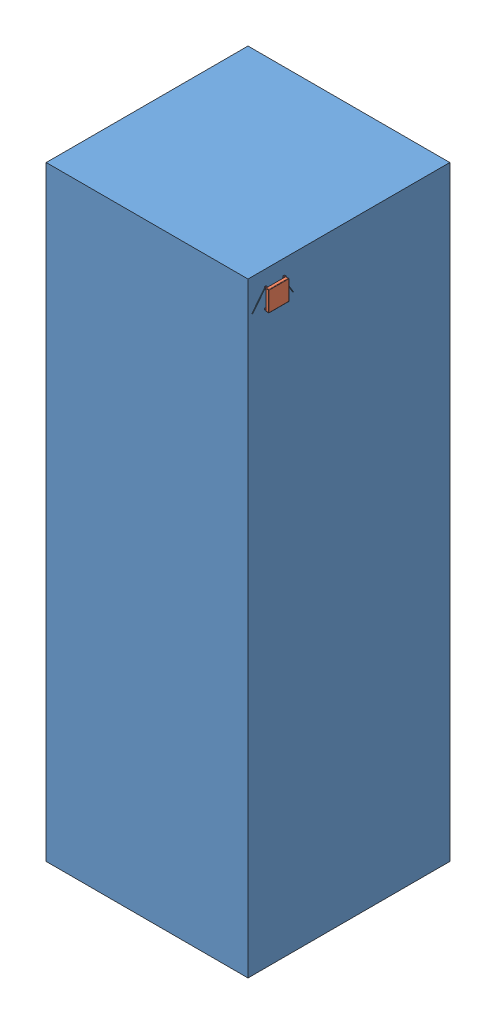
SolidWorks assembly with_building, configuration Default. Lengths in mm.
Overall size (10270 30000 10000).
10 component instances, 5 part files, 4 mates.
Components (placement in the parent):
- gedung-1: gedung [Default] at (-1.2528 -15032.5087 22.747) size (10000 30000 10000)
- full_coreXY_ass-1: full_coreXY_ass [Default] at (5184.5696 13734.8256 3801.1305) x (0 0 1) z (0 1 0) size (2041.12 273.73 1048.26) (flexible)
  - body-1: body [Default] at (-44.1875 -65.8225 17.0821) size (1000 150 1000)
  - brush-1: brush [Default] at (-44.1875 34.1775 17.0821) x (0.681029 0 -0.732256) z (-0.732256 0 -0.681029) size (741.72 210 741.72)
  - swivel-1: swivel [Default] at (377.6119 -153.5116 -450.8674) size (121.23 123.73 64.1)
  - swivel-2: swivel [Default] at (377.6119 -153.5116 485.0302) size (121.23 123.73 64.1)
  - swivel-6: swivel [Default] at (-546.5145 -153.5116 -450.8674) size (121.23 123.73 64.1)
  - swivel-7: swivel [Default] at (-546.5145 -153.5116 485.0302) size (121.23 123.73 64.1)
  - wiper-1: wiper [Default] at (714.4345 -185.8225 34.9173) x (0.615715 0 -0.787969) z (0.787969 0 0.615715) size (1000 220 20)
  - wiper-2: wiper [Default] at (-749.463 -185.8225 -1.3256) x (-0.505723 0 -0.862696) z (0.862696 0 -0.505723) size (1000 220 20)
Mates (geometry in assembly coordinates):
- Parallel1: parallel aligned: plane of gedung-1 through (-1.2528 14967.4913 22.747) normal (0 1 0); plane of full_coreXY_ass-1/body-1 through (5268.7472 14251.9077 3256.943) normal (0 1 0)
- Coincident2: coincident anti-aligned: plane of gedung-1 through (4998.7472 14967.4913 -4977.253) normal (1 0 0); plane of full_coreXY_ass-1/wiper-2 through (4998.7472 13733.5 3051.6675) normal (-1 0 0)
- LimitDistance1: limit distance = 765.804 mm aligned: plane of full_coreXY_ass-1/body-1 through (5268.7472 13251.9077 4256.943) normal (0 0 1); plane of gedung-1 through (-5001.2528 14967.4913 5022.747) normal (0 0 1)
- LimitDistance2: limit distance = 715.5837 mm aligned: plane of full_coreXY_ass-1/body-1 through (5268.7472 14251.9077 3256.943) normal (0 1 0); plane of gedung-1 through (-1.2528 14967.4913 22.747) normal (0 1 0)
